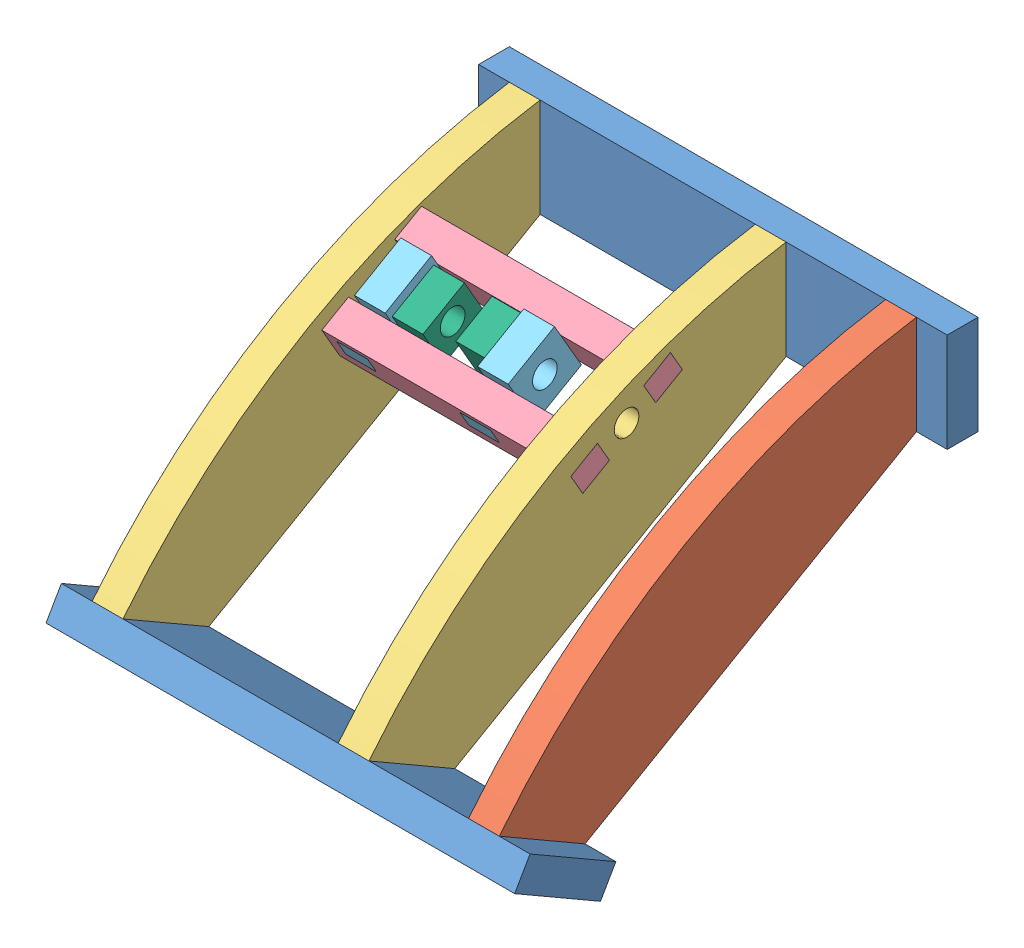
SolidWorks assembly outerFootAssembly2, configuration Default. Lengths in mm.
Overall size (78.4 62.14 85.64).
11 component instances, 6 part files, 25 mates.
Components (placement in the parent):
- OuterActuatorSidePlate-1: OuterActuatorSidePlate [Default] at (-38.043 5.3284 -12.4367) size (78.4 16.58 5.15)
- SpanningPlate-1: SpanningPlate [Default] at (30.057 -86.882 -23.5738) x (0 0.5 -0.866025) z (1 0 0) size (86.18 22 5.15)
- ConnectingPlate-1: ConnectingPlate [Default] at (8.257 -86.882 -23.5738) x (0 0.5 -0.866025) z (1 0 0) size (86.18 22 5.15)
- ConnectingPlate-2: ConnectingPlate [Default] at (-32.893 -86.882 -23.5738) x (0 0.5 -0.866025) z (1 0 0) size (86.18 22 5.15)
- OuterActuatorSpanner-1: OuterActuatorSpanner [Default] at (-9.743 4.1974 21.7731) x (1 0 0) z (0 -0.5 0.866025) size (46.3 6 5.15)
- OuterActuatorSpanner-2: OuterActuatorSpanner [Default] at (-9.743 11.2443 9.5676) x (1 0 0) z (0 -0.5 0.866025) size (46.3 6 5.15)
- SpacerBoltConnector-1: SpacerBoltConnector [Default] at (-5.168 0.7564 25.7331) x (0 0.5 -0.866025) z (1 0 0) size (19.24 9 5.15)
- A-Spacer-1: A-Spacer [Default] at (-10.318 8.0002 14.1866) x (0 0.866025 0.5) z (1 0 0) size (8 7 5.15)
- OuterActuatorSidePlate-2: OuterActuatorSidePlate [Default] at (-38.043 -26.6717 48.1392) x (1 0 0) z (0 -0.866025 0.5) size (78.4 16.58 5.15)
- A-Spacer-2: A-Spacer [Default] at (-15.443 8.0002 14.1866) x (0 -0.5 0.866025) z (-1 0 0) size (8 7 5.15)
- SpacerBoltConnector-2: SpacerBoltConnector [Default] at (-20.593 8.5506 30.2331) x (0 0.5 -0.866025) z (-1 0 0) size (19.24 9 5.15)
Mates (geometry in assembly coordinates):
- Coincident15: coincident aligned: line of OuterActuatorSidePlate-1 through (35.207 18.59 -12.4367) axis (-1 0 0); line of SpanningPlate-1 through (35.207 18.59 -12.4367) axis (-1 0 0)
- Coincident16: coincident aligned: line of OuterActuatorSidePlate-1 through (35.207 15.2746 -12.4367) axis (0 1 0); line of SpanningPlate-1 through (35.207 15.2746 -12.4367) axis (0 1 0)
- Coincident23: coincident anti-aligned: line of ConnectingPlate-1 through (13.407 -26.1586 59.3278) axis (-1 0 0); line of OuterActuatorSidePlate-2 through (8.257 -26.1586 59.3278) axis (1 0 0)
- Coincident24: coincident anti-aligned: line of ConnectingPlate-1 through (13.407 -24.5009 62.1991) axis (0 -0.5 -0.866025); line of OuterActuatorSidePlate-2 through (13.407 -26.1586 59.3278) axis (0 0.5 0.866025)
- Coincident25: coincident aligned: line of SpanningPlate-1 through (35.207 -24.5009 62.1991) axis (-1 0 0); line of OuterActuatorSidePlate-2 through (35.207 -24.5009 62.1991) axis (-1 0 0)
- Coincident26: coincident anti-aligned: line of SpanningPlate-1 through (35.207 -24.5009 62.1991) axis (0 -0.5 -0.866025); line of OuterActuatorSidePlate-2 through (35.207 -26.1586 59.3278) axis (0 0.5 0.866025)
- Coincident28: coincident anti-aligned: line of ConnectingPlate-2 through (-27.743 -29.4741 53.5853) axis (-1 0 0); line of OuterActuatorSidePlate-2 through (-32.893 -29.474 53.5854) axis (1 0 0)
- Coincident29: coincident anti-aligned: line of ConnectingPlate-2 through (-27.743 -27.8163 56.4566) axis (0 -0.5 -0.866025); line of OuterActuatorSidePlate-2 through (-27.743 -29.474 53.5854) axis (0 0.5 0.866025)
- Coincident30: coincident anti-aligned: line of ConnectingPlate-2 through (-32.893 15.5744 12.0676) axis (0 -0.5 0.866025); line of OuterActuatorSpanner-2 through (-32.893 12.9994 16.5277) axis (0 0.5 -0.866025)
- Coincident31: coincident anti-aligned: line of ConnectingPlate-2 through (-32.893 12.1103 10.0676) axis (0 0.866025 0.5); line of OuterActuatorSpanner-2 through (-32.893 15.5744 12.0676) axis (0 -0.866025 -0.5)
- Coincident32: coincident anti-aligned: line of ConnectingPlate-2 through (-32.893 8.5276 24.2731) axis (0 -0.5 0.866025); line of OuterActuatorSpanner-1 through (-32.893 5.9526 28.7331) axis (0 0.5 -0.866025)
- Coincident34: coincident aligned: line of ConnectingPlate-2 through (-32.893 5.9526 28.7331) axis (0 -0.866025 -0.5); line of OuterActuatorSpanner-1 through (-32.893 5.9526 28.7331) axis (0 -0.866025 -0.5)
- Coincident35: coincident aligned: line of OuterActuatorSpanner-1 through (-5.168 5.9526 28.7331) axis (0 -0.866025 -0.5); line of SpacerBoltConnector-1 through (-5.168 5.9526 28.7331) axis (0 -0.866025 -0.5)
- Coincident36: coincident aligned: line of OuterActuatorSpanner-1 through (-0.018 5.9526 28.7331) axis (-1 0 0); line of SpacerBoltConnector-1 through (-0.018 5.9526 28.7331) axis (-1 0 0)
- Concentric1: concentric aligned: cylinder of SpacerBoltConnector-1 through (-5.168 9.4643 19.6507) axis (1 0 0) radius 2.0675; cylinder of A-Spacer-1 through (-10.318 9.4643 19.6507) axis (1 0 0) radius 2.0675
- Coincident37: coincident anti-aligned: plane of SpacerBoltConnector-1 through (-5.168 5.9295 22.7731) normal (-1 0 0); plane of A-Spacer-1 through (-5.168 8.0002 14.1866) normal (1 0 0)
- Parallel2: parallel aligned: plane of SpacerBoltConnector-1 through (-0.018 15.5971 18.0282) normal (0 0.866025 0.5); plane of A-Spacer-1 through (-5.168 14.9284 18.1866) normal (0 0.866025 0.5)
- Coincident40: coincident anti-aligned: line of OuterActuatorSpanner-2 through (-20.593 12.9763 10.5676) axis (0 0.866025 0.5); line of SpacerBoltConnector-2 through (-20.593 15.5741 12.0682) axis (0 -0.866025 -0.5)
- Coincident41: coincident: line of OuterActuatorSpanner-2 through (-25.743 12.9763 10.5676) axis (1 0 0); moEndPointRef_w of SpacerBoltConnector-2
- Concentric2: concentric aligned: cylinder of A-Spacer-2 through (-15.443 9.4643 19.6507) axis (-1 0 0) radius 2.0675; cylinder of SpacerBoltConnector-2 through (-20.593 9.4643 19.6507) axis (-1 0 0) radius 2.0675
- Coincident42: coincident anti-aligned: plane of A-Spacer-2 through (-20.593 8.0002 14.1866) normal (-1 0 0); plane of SpacerBoltConnector-2 through (-20.593 8.5276 24.2731) normal (1 0 0)
- Concentric3: concentric anti-aligned: cylinder of A-Spacer-1 through (-10.318 9.4643 19.6507) axis (1 0 0) radius 2.0675; cylinder of A-Spacer-2 through (-15.443 9.4643 19.6507) axis (-1 0 0) radius 2.0675
- Parallel3: parallel aligned: plane of A-Spacer-1 through (-5.168 14.9284 18.1866) normal (0 0.866025 0.5); plane of A-Spacer-2 through (-20.593 10.0624 24.6148) normal (0 0.866025 0.5)
- Coincident44: coincident aligned: line of ConnectingPlate-1 through (13.407 9.5353 14.5277) axis (0 0.5 -0.866025); line of OuterActuatorSpanner-2 through (13.407 9.5353 14.5277) axis (0 0.5 -0.866025)
- Coincident45: coincident anti-aligned: line of ConnectingPlate-2 through (-27.743 -26.1586 59.3278) axis (-1 0 0); line of OuterActuatorSidePlate-2 through (-32.893 -26.1586 59.3278) axis (1 0 0)
